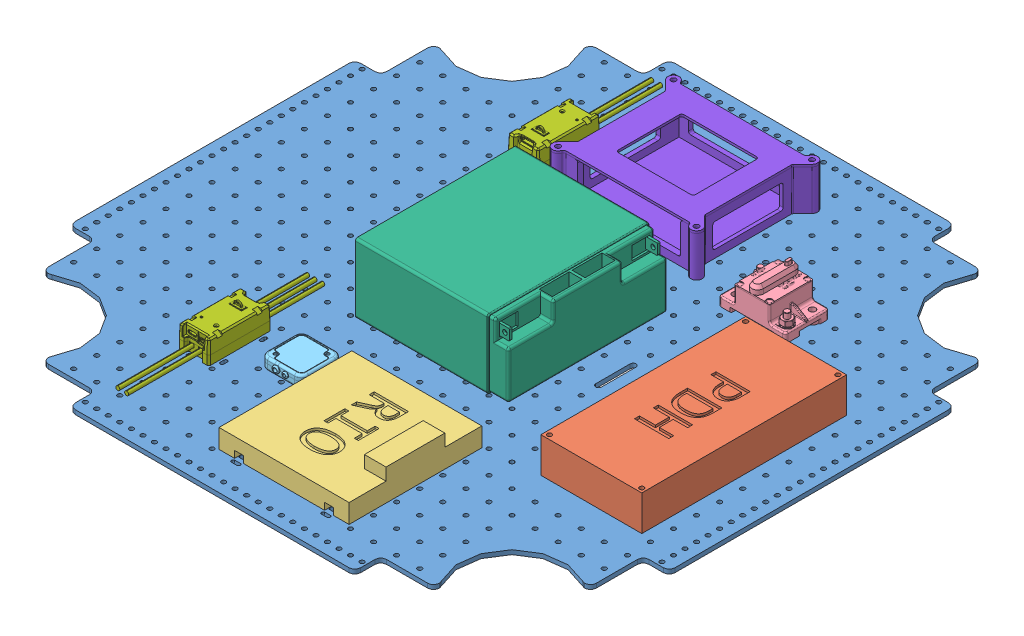
SolidWorks assembly electronics, configuration Default. Lengths in mm.
Overall size (660.4 80.95 660.4).
9 component instances, 8 part files, 26 mates.
Components (placement in the parent):
- 599-23-OFFSEASON-DT-P-0003-1: 599-23-OFFSEASON-DT-P-0003 [.187] at origin size (660.4 4.75 660.4)
- PDH-min-1: PDH-min [Default] at (498.5 21.7614 -419.1) x (0 0 1) z (-1 0 0) size (225.4 38.77 111.1)
- ROBORIO-min-1: ROBORIO-min [Default] at (296.5577 19.5834 -187.4266) x (0 0 1) z (-1 0 0) size (146.15 34.42 143.18)
- Main Breaker-1: Main Breaker [Default] at (471.17 7.2009 -477.52) x (-1 0 0) z (0 0 -1) size (73.7 42.15 48.27)
- Pigeon 2-2: Pigeon 2 [Default] at (263.779 9.2205 -164.9476) x (1 0 0) z (0 -1 0) size (44.96 46.94 12.96)
- Battery-1: Battery [Default] at (246.634 64.5881 -274.4131) x (0 0 -1) z (1 0 0) size (177.8 76.2 167.14)
- Spark Max REV-11-2158-1: Spark Max REV-11-2158 [Default] at (195.05 25.3249 -511.475) x (0 0 1) z (1 0 0) size (212.48 29.65 34.5)
- Spark Max REV-11-2158-2: Spark Max REV-11-2158 [Default] at (195.05 25.3249 -148.925) x (0 0 -1) z (-1 0 0) size (212.48 29.65 34.5)
- beelink case body-1: beelink case body [Default] at (247.65 46.8249 -469.9) x (0 0 -1) z (-1 0 0) size (139.7 46.99 165.1)
Mates (geometry in assembly coordinates):
- Coincident1: coordinate: point of 599-23-OFFSEASON-DT-P-0003-1
- Coincident3: coincident anti-aligned: plane of 599-23-OFFSEASON-DT-P-0003-1 through (0 2.3749 0) normal (0 1 0); plane of ROBORIO-min-1 through (296.5577 2.3749 -187.4266) normal (0 -1 0)
- Parallel1: parallel aligned: plane of 599-23-OFFSEASON-DT-P-0003-1 through (660.4 2.3749 0) normal (1 0 0); plane of Pigeon 2-2 through (286.258 14.1097 -150.0886) normal (1 0 0)
- Coincident4: coincident anti-aligned: plane of 599-23-OFFSEASON-DT-P-0003-1 through (0 2.3749 0) normal (0 1 0); plane of Pigeon 2-2 through (278.638 2.3749 -150.0886) normal (0 -1 0)
- Coincident5: coincident anti-aligned: plane of 599-23-OFFSEASON-DT-P-0003-1 through (0 2.3749 0) normal (0 1 0); plane of Main Breaker-1 through (501.6925 2.3749 -497.8907) normal (0 -1 0)
- Coincident7: coincident anti-aligned: plane of 599-23-OFFSEASON-DT-P-0003-1 through (0 2.3749 0) normal (0 1 0); plane of PDH-min-1 through (498.5 2.3749 -419.1) normal (0 -1 0)
- Coincident8: coincident anti-aligned: plane of 599-23-OFFSEASON-DT-P-0003-1 through (0 2.3749 0) normal (0 1 0); plane of Battery-1 through (398.653 2.3749 -235.204) normal (0 -1 0)
- Width1: width anti-aligned: plane of 599-23-OFFSEASON-DT-P-0003-1 through (0 2.3749 0) normal (-1 0 0); plane of 599-23-OFFSEASON-DT-P-0003-1 through (660.4 2.3749 0) normal (1 0 0); plane of Battery-1 through (413.766 2.984 -236.8291) normal (1 0 0); plane of Battery-1 through (246.634 -1.4351 -232.41) normal (-1 0 0)
- Width2: width anti-aligned: plane of 599-23-OFFSEASON-DT-P-0003-1 through (0 2.3749 0) normal (0 0 1); plane of 599-23-OFFSEASON-DT-P-0003-1 through (0 2.3749 -660.4) normal (0 0 -1); plane of Battery-1 through (398.653 1.3589 -419.1) normal (0 0 -1); plane of Battery-1 through (239.395 1.3589 -241.3) normal (0 0 1)
- Distance5: distance = 41.275 mm aligned: plane of ROBORIO-min-1 through (296.5577 36.7919 -41.275) normal (0 0 1); plane of 599-23-OFFSEASON-DT-P-0003-1 through (0 2.3749 0) normal (0 0 1)
- Distance6: distance = 47.625 mm aligned: plane of ROBORIO-min-1 through (439.7375 36.7919 -187.4266) normal (1 0 0); plane of 599-23-OFFSEASON-DT-P-0003-1 through (487.3625 2.3749 0) normal (1 0 0)
- Distance7: distance = 50.8 mm aligned: plane of PDH-min-1 through (609.6 41.148 -419.1) normal (1 0 0); plane of 599-23-OFFSEASON-DT-P-0003-1 through (660.4 2.3749 0) normal (1 0 0)
- Distance8: distance = 158.75 mm aligned: plane of Main Breaker-1 through (471.17 9.7409 -501.65) normal (0 0 -1); plane of 599-23-OFFSEASON-DT-P-0003-1 through (0 2.3749 -660.4) normal (0 0 -1)
- Coincident16: coincident aligned: plane of ROBORIO-min-1 through (296.5577 36.7919 -187.4266) normal (0 0 -1); plane of Pigeon 2-2 through (278.638 14.1097 -187.4266) normal (0 0 -1)
- Distance9: distance = 241.3 mm aligned: plane of Pigeon 2-2 through (241.3 14.1097 -179.8066) normal (-1 0 0); plane of 599-23-OFFSEASON-DT-P-0003-1 through (0 2.3749 0) normal (-1 0 0)
- Coincident18: coincident aligned: plane of PDH-min-1 through (498.5 41.148 -419.1) normal (0 0 -1); plane of Battery-1 through (398.653 1.3589 -419.1) normal (0 0 -1)
- Distance10: distance = 152.4 mm aligned: plane of Main Breaker-1 through (508 7.2009 -477.52) normal (1 0 0); plane of 599-23-OFFSEASON-DT-P-0003-1 through (660.4 2.3749 0) normal (1 0 0)
- Coincident20: coincident anti-aligned: plane of 599-23-OFFSEASON-DT-P-0003-1 through (0 2.3749 0) normal (0 1 0); plane of Spark Max REV-11-2158-1 through (195.05 2.3749 -511.475) normal (0 -1 0)
- Coincident21: coincident anti-aligned: plane of 599-23-OFFSEASON-DT-P-0003-1 through (0 2.3749 0) normal (0 1 0); plane of Spark Max REV-11-2158-2 through (195.05 2.3749 -148.925) normal (0 -1 0)
- Coincident22: coincident anti-aligned: plane of 599-23-OFFSEASON-DT-P-0003-1 through (0 2.3749 0) normal (0 1 0); plane of beelink case body-1 through (247.65 2.3749 -469.9) normal (0 -1 0)
- Concentric2: concentric aligned: cylinder of 599-23-OFFSEASON-DT-P-0003-1 through (393.7 -2.3749 -596.9) axis (0 1 0) radius 2.4892; cylinder of beelink case body-1 through (393.7 2.3749 -596.9) axis (0 1 0) radius 2.794
- Concentric3: concentric aligned: cylinder of 599-23-OFFSEASON-DT-P-0003-1 through (393.7 -2.3749 -469.9) axis (0 1 0) radius 2.4892; cylinder of beelink case body-1 through (393.7 2.3749 -469.9) axis (0 1 0) radius 2.794
- Distance11: distance = 114.3 mm aligned: plane of Spark Max REV-11-2158-1 through (177.8 12.8249 -546.1) normal (0 0 -1); plane of 599-23-OFFSEASON-DT-P-0003-1 through (0 2.3749 -660.4) normal (0 0 -1)
- Distance12: distance = 114.3 mm aligned: plane of Spark Max REV-11-2158-2 through (212.3 12.8249 -114.3) normal (0 0 1); plane of 599-23-OFFSEASON-DT-P-0003-1 through (0 2.3749 0) normal (0 0 1)
- Coincident25: coincident aligned: plane of Spark Max REV-11-2158-1 through (177.8 12.8249 -546.1) normal (-1 0 0); plane of Spark Max REV-11-2158-2 through (177.8 12.8249 -114.3) normal (-1 0 0)
- Distance13: distance = 177.8 mm aligned: plane of Spark Max REV-11-2158-1 through (177.8 12.8249 -546.1) normal (-1 0 0); plane of 599-23-OFFSEASON-DT-P-0003-1 through (0 2.3749 0) normal (-1 0 0)
